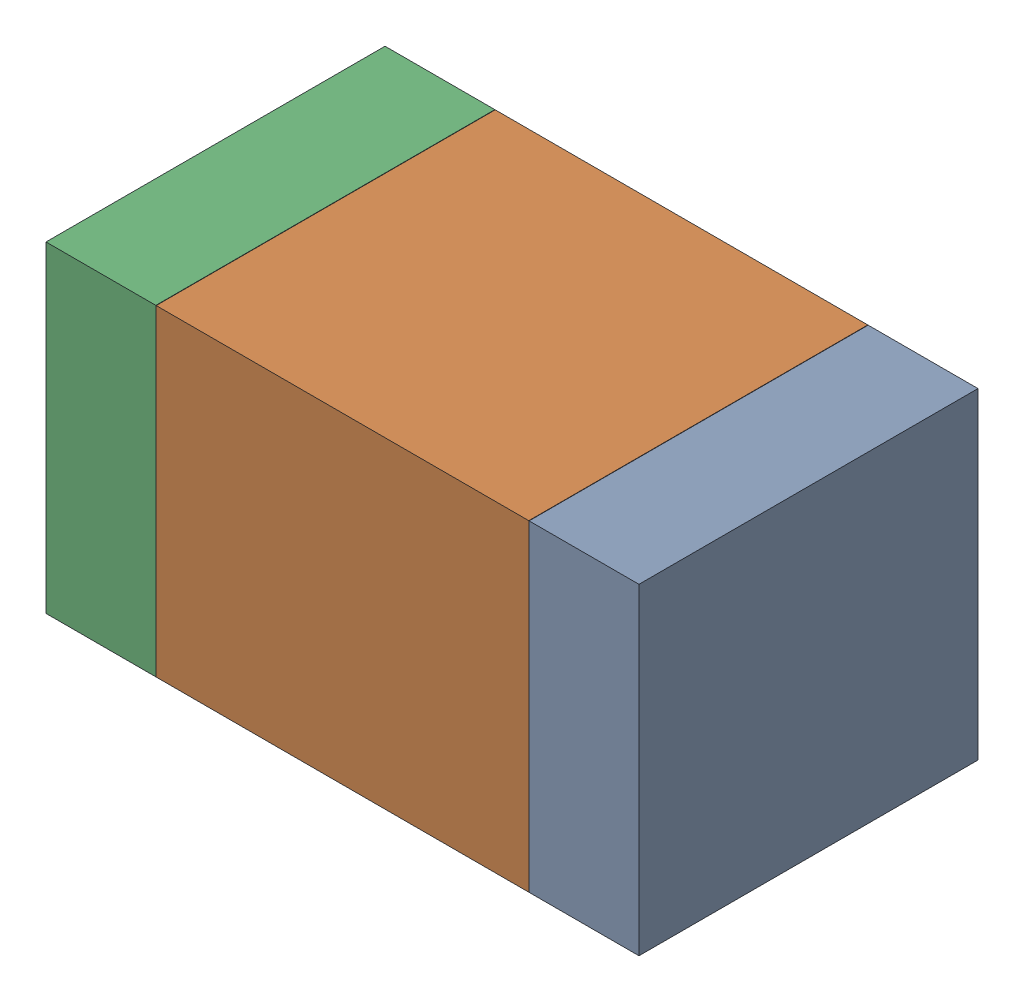
SolidWorks assembly R17, configuration Default. Lengths in mm.
Overall size (1.75 0.95 1).
6 component instances, 2 part files, 0 mates.
Components (placement in the parent):
- 6575498272-1: 6575498272 [Default] at (16.7145 14.478 0) size (0.32 0.95 1)
  - Extruded_8-1: Extruded_8 [Default] at origin size (0.32 0.95 1)
- 6575498112-1: 6575498112 [Default] at (16.002 14.478 0) size (1.1 0.95 1)
  - Extruded_9-1: Extruded_9 [Default] at origin size (1.1 0.95 1)
- 6575498272-2: 6575498272 [Default] at (15.2895 14.478 0) size (0.32 0.95 1)
  - Extruded_8-1: Extruded_8 [Default] at origin size (0.32 0.95 1)
